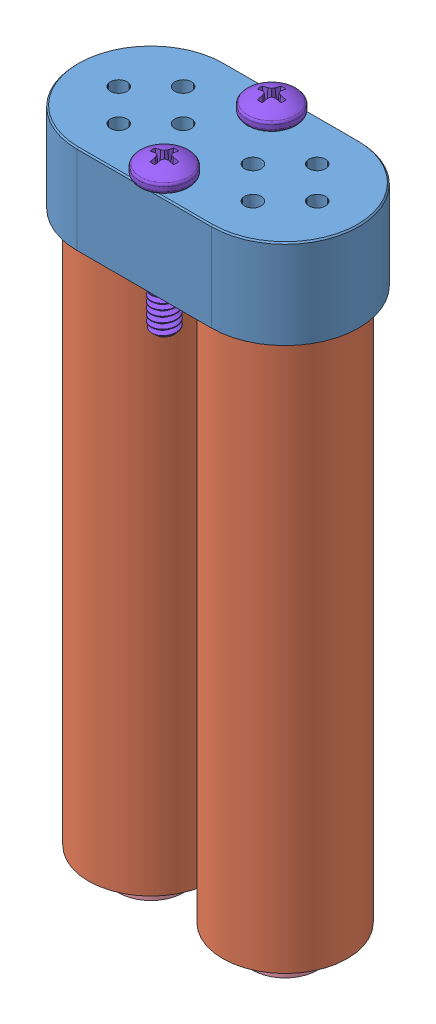
SolidWorks assembly S1B_Peregrine_Assembly, configuration Default. Lengths in mm.
Overall size (53.34 129.45 29.79).
15 component instances, 8 part files, 43 mates.
Components (placement in the parent):
- S1B_Peregrine_DualPeregrine_CO2_System_Cap-1: S1B_Peregrine_DualPeregrine_CO2_System_Cap [Default] at origin size (53.34 16.87 27.94)
- S1B_Peregrine_CO2_System_Tube-1: S1B_Peregrine_CO2_System_Tube [Default] at origin size (23.62 104.52 23.62)
- S1B_Peregrine_CO2_System_Tube-2: S1B_Peregrine_CO2_System_Tube [Default] at (25.4 0 0) size (23.62 104.52 23.62)
- S1B_Peregrine_Capsule-2: S1B_Peregrine_Capsule [Default] at (25.4 -87.884 0) size (18.64 82.88 18.64)
- S1B_Peregrine_Capsule-3: S1B_Peregrine_Capsule [Default] at (0 -87.884 0) size (18.64 82.88 18.64)
- S1B_Peregrine_Charge_Cup-1: S1B_Peregrine_Charge_Cup [Default] at (25.4 -109.2708 0) size (18.85 16.36 18.85)
- S1B_Peregrine_Charge_Cup-2: S1B_Peregrine_Charge_Cup [Default] at (0 -109.2708 0) size (18.85 16.36 18.85)
- S1B_Peregrine_Lift_Piston-1: S1B_Peregrine_Lift_Piston [Default] at (25.4 -92.9132 0) size (20.08 9.25 20.08)
- S1B_Peregrine_Lift_Piston-2: S1B_Peregrine_Lift_Piston [Default] at (0 -92.9132 0) size (20.08 9.25 20.08)
- S1B_Peregrine_Alignment_Collar-1: S1B_Peregrine_Alignment_Collar [Default] at (25.4 -8.89 0) x (-1 0 0) z (0 0 1) size (18.8 9.7 18.8)
- S1B_Peregrine_Alignment_Collar-2: S1B_Peregrine_Alignment_Collar [Default] at (0 -8.89 0) x (-1 0 0) z (0 0 1) size (18.8 9.7 18.8)
- S1B_Peregrine_Spring-1: S1B_Peregrine_Spring [Default] at (25.4 -8.89 0) size (18.69 11.43 17.78)
- S1B_Peregrine_Spring-2: S1B_Peregrine_Spring [Default] at (0 -8.89 0) size (18.69 11.43 17.78)
- S1B_Peregrine_DualPeregrine_Mounting_Bolt_91772A247_Passivated 18-8 Stainless Steel Pan Head Phillips Screw-1: S1B_Peregrine_DualPeregrine_Mounting_Bolt_91772A247_Passivated 18-8 Stainless Steel Pan Head Phillips Screw [91772A247] at (12.7 -8.5344 -10.16) x (-1 0 0) z (0 1 0) size (9.47 9.47 28.89)
- S1B_Peregrine_DualPeregrine_Mounting_Bolt_91772A247_Passivated 18-8 Stainless Steel Pan Head Phillips Screw-2: S1B_Peregrine_DualPeregrine_Mounting_Bolt_91772A247_Passivated 18-8 Stainless Steel Pan Head Phillips Screw [91772A247] at (12.7 -8.5344 10.16) x (1 0 0) z (0 1 0) size (9.47 9.47 28.89)
Mates (geometry in assembly coordinates):
- Coincident1: coincident aligned: line of S1B_Peregrine_DualPeregrine_CO2_System_Cap-1 through (16.6116 0 16.6116) axis (0 0 -1); line of S1B_Peregrine_CO2_System_Tube-1 through (114.9731 0 5.2261) axis (0 0 -1)
- Coincident2: coincident aligned: line of S1B_Peregrine_DualPeregrine_CO2_System_Cap-1 through (16.6116 25.4 16.6116) axis (0 0 -1); line of S1B_Peregrine_CO2_System_Tube-2 through (114.9731 25.4 5.2261) axis (0 0 -1)
- Coincident3: coincident anti-aligned: plane of S1B_Peregrine_DualPeregrine_CO2_System_Cap-1 through (0 0 0) normal (0 -1 0); plane of S1B_Peregrine_CO2_System_Tube-1 through (0 0 0) normal (0 1 0)
- Coincident4: coincident anti-aligned: plane of S1B_Peregrine_DualPeregrine_CO2_System_Cap-1 through (0 0 0) normal (0 -1 0); plane of S1B_Peregrine_CO2_System_Tube-2 through (25.4 0 0) normal (0 1 0)
- Parallel1: parallel aligned: plane of S1B_Peregrine_CO2_System_Tube-1 through (0 0 0) normal (0 0 1)
- Parallel2: parallel aligned: plane of S1B_Peregrine_CO2_System_Tube-2 through (25.4 0 0) normal (0 0 1)
- Concentric1: concentric aligned: line of S1B_Peregrine_DualPeregrine_CO2_System_Cap-1 through (16.6116 25.4 16.6116) axis (0 0 -1); cylinder of S1B_Peregrine_Capsule-2 through (25.4 -5.0038 0) axis (0 -1 0) radius 9.3218
- Concentric2: concentric aligned: line of S1B_Peregrine_DualPeregrine_CO2_System_Cap-1 through (16.6116 0 16.6116) axis (0 0 -1); cylinder of S1B_Peregrine_Capsule-3 through (0 -5.0038 0) axis (0 -1 0) radius 9.3218
- Parallel3: parallel aligned: plane of S1B_Peregrine_Capsule-2 through (25.4 -87.884 0) normal (0 0 1)
- Parallel4: parallel aligned: plane of S1B_Peregrine_Capsule-2 through (25.4 -87.884 0) normal (0 0 1)
- Parallel5: parallel aligned: plane of S1B_Peregrine_Capsule-3 through (0 -87.884 0) normal (0 0 1)
- Coincident5: coincident aligned: line of S1B_Peregrine_DualPeregrine_CO2_System_Cap-1 through (16.6116 25.4 16.6116) axis (0 0 -1); line of S1B_Peregrine_Charge_Cup-1 through (17.9934 25.4 -92.0953) axis (0 0 -1)
- Coincident6: coincident aligned: line of S1B_Peregrine_DualPeregrine_CO2_System_Cap-1 through (16.6116 0 16.6116) axis (0 0 -1); line of S1B_Peregrine_Charge_Cup-2 through (17.9934 0 -92.0953) axis (0 0 -1)
- Parallel6: parallel aligned: plane of S1B_Peregrine_Charge_Cup-2 through (0 -109.2708 0) normal (0 0 1)
- Parallel7: parallel aligned: plane of S1B_Peregrine_Charge_Cup-1 through (25.4 -109.2708 0) normal (0 0 1)
- Coincident7: coincident anti-aligned: plane of S1B_Peregrine_CO2_System_Tube-1 through (0 -99.441 0) normal (0 1 0); plane of S1B_Peregrine_Charge_Cup-2 through (9.4234 -99.441 0) normal (0 -1 0)
- Coincident8: coincident anti-aligned: plane of S1B_Peregrine_CO2_System_Tube-2 through (25.4 -99.441 0) normal (0 1 0); plane of S1B_Peregrine_Charge_Cup-1 through (34.8234 -99.441 0) normal (0 -1 0)
- Coincident9: coincident anti-aligned: line of S1B_Peregrine_DualPeregrine_CO2_System_Cap-1 through (16.6116 25.4 16.6116) axis (0 0 -1); line of S1B_Peregrine_Lift_Piston-1 through (10.1702 25.4 -93.3755) axis (0 0 1)
- Coincident10: coincident anti-aligned: line of S1B_Peregrine_DualPeregrine_CO2_System_Cap-1 through (16.6116 0 16.6116) axis (0 0 -1); line of S1B_Peregrine_Lift_Piston-2 through (10.1702 0 -93.3755) axis (0 0 1)
- Coincident11: coincident aligned: plane of S1B_Peregrine_Lift_Piston-2 through (0 -92.9132 0) normal (0 0 1)
- Coincident12: coincident aligned: plane of S1B_Peregrine_Lift_Piston-1 through (25.4 -92.9132 0) normal (0 0 1)
- Coincident13: coincident anti-aligned: plane of S1B_Peregrine_Charge_Cup-2 through (9.4234 -92.9132 0) normal (0 1 0); plane of S1B_Peregrine_Lift_Piston-2 through (0 -92.9132 0) normal (0 -1 0)
- Coincident14: coincident anti-aligned: plane of S1B_Peregrine_Charge_Cup-1 through (34.8234 -92.9132 0) normal (0 1 0); plane of S1B_Peregrine_Lift_Piston-1 through (25.4 -92.9132 0) normal (0 -1 0)
- Coincident15: coincident aligned: plane of S1B_Peregrine_Capsule-2 through (25.4 -87.884 0) normal (0 1 0); plane of S1B_Peregrine_Capsule-3 through (0 -87.884 0) normal (0 1 0)
- Distance1: distance = 87.884 mm aligned: plane of S1B_Peregrine_Capsule-3 through (0 -87.884 0) normal (0 1 0)
- Coincident16: coincident aligned: line of S1B_Peregrine_DualPeregrine_CO2_System_Cap-1 through (16.6116 25.4 16.6116) axis (0 0 -1); line of S1B_Peregrine_Alignment_Collar-1 through (25.4 -8.4049 0) axis (0 -1 0)
- Coincident17: coincident aligned: line of S1B_Peregrine_DualPeregrine_CO2_System_Cap-1 through (16.6116 0 16.6116) axis (0 0 -1); line of S1B_Peregrine_Alignment_Collar-2 through (0 -8.4049 0) axis (0 -1 0)
- Parallel8: parallel aligned: plane of S1B_Peregrine_Alignment_Collar-1 through (25.4 -8.89 0) normal (0 0 1)
- Parallel9: parallel aligned: plane of S1B_Peregrine_Alignment_Collar-2 through (0 -8.89 0) normal (0 0 1)
- Coincident18: coincident aligned: plane of S1B_Peregrine_Alignment_Collar-1 through (25.4 -8.89 0) normal (0 -1 0); plane of S1B_Peregrine_Alignment_Collar-2 through (0 -8.89 0) normal (0 -1 0)
- Distance2: distance = 8.89 mm anti-aligned: plane of S1B_Peregrine_Alignment_Collar-2 through (0 -8.89 0) normal (0 -1 0)
- Coincident19: coincident anti-aligned: line of S1B_Peregrine_DualPeregrine_CO2_System_Cap-1 through (16.6116 25.4 16.6116) axis (0 0 -1); line of S1B_Peregrine_Spring-1 through (36.6014 25.4 -11.8237) axis (0 0 1)
- Coincident20: coincident anti-aligned: line of S1B_Peregrine_DualPeregrine_CO2_System_Cap-1 through (16.6116 0 16.6116) axis (0 0 -1); line of S1B_Peregrine_Spring-2 through (36.6014 0 -11.8237) axis (0 0 1)
- Parallel10: parallel aligned: plane of S1B_Peregrine_Spring-2 through (0 -8.89 0) normal (0 0 1)
- Parallel11: parallel aligned: plane of S1B_Peregrine_Spring-1 through (25.4 -8.89 0) normal (0 0 1)
- Coincident21: coincident aligned: plane of S1B_Peregrine_Spring-1 through (25.4 -8.89 0) normal (0 1 0); plane of S1B_Peregrine_Spring-2 through (0 -8.89 0) normal (0 1 0)
- Coincident22: coincident aligned: plane of S1B_Peregrine_Alignment_Collar-1 through (25.4 -8.89 0) normal (0 1 0); plane of S1B_Peregrine_Spring-1 through (25.4 -8.89 0) normal (0 1 0)
- Concentric4: concentric aligned: cylinder of S1B_Peregrine_DualPeregrine_CO2_System_Cap-1 through (12.7 0 -10.16) axis (0 1 0) radius 2.286; line of S1B_Peregrine_DualPeregrine_Mounting_Bolt_91772A247_Passivated 18-8 Stainless Steel Pan Head Phillips Screw-1 through (12.7 -10.1523 -10.16) axis (0 1 0)
- Concentric3: concentric aligned: cylinder of S1B_Peregrine_DualPeregrine_CO2_System_Cap-1 through (12.7 0 10.16) axis (0 1 0) radius 2.286; line of S1B_Peregrine_DualPeregrine_Mounting_Bolt_91772A247_Passivated 18-8 Stainless Steel Pan Head Phillips Screw-2 through (12.7 -10.1523 10.16) axis (0 1 0)
- Coincident24: coincident anti-aligned: plane of S1B_Peregrine_DualPeregrine_CO2_System_Cap-1 through (0 16.8656 0) normal (0 1 0); plane of S1B_Peregrine_DualPeregrine_Mounting_Bolt_91772A247_Passivated 18-8 Stainless Steel Pan Head Phillips Screw-2 through (12.7 16.8656 10.16) normal (0 -1 0)
- Coincident25: coincident anti-aligned: plane of S1B_Peregrine_DualPeregrine_CO2_System_Cap-1 through (0 16.8656 0) normal (0 1 0); plane of S1B_Peregrine_DualPeregrine_Mounting_Bolt_91772A247_Passivated 18-8 Stainless Steel Pan Head Phillips Screw-1 through (12.7 16.8656 -10.16) normal (0 -1 0)
- Parallel12: parallel aligned: plane of S1B_Peregrine_DualPeregrine_Mounting_Bolt_91772A247_Passivated 18-8 Stainless Steel Pan Head Phillips Screw-1 through (12.7 -8.5344 -10.16) normal (0 0 1)
- Parallel13: parallel anti-aligned: plane of S1B_Peregrine_DualPeregrine_Mounting_Bolt_91772A247_Passivated 18-8 Stainless Steel Pan Head Phillips Screw-2 through (12.7 -8.5344 10.16) normal (0 0 -1)
